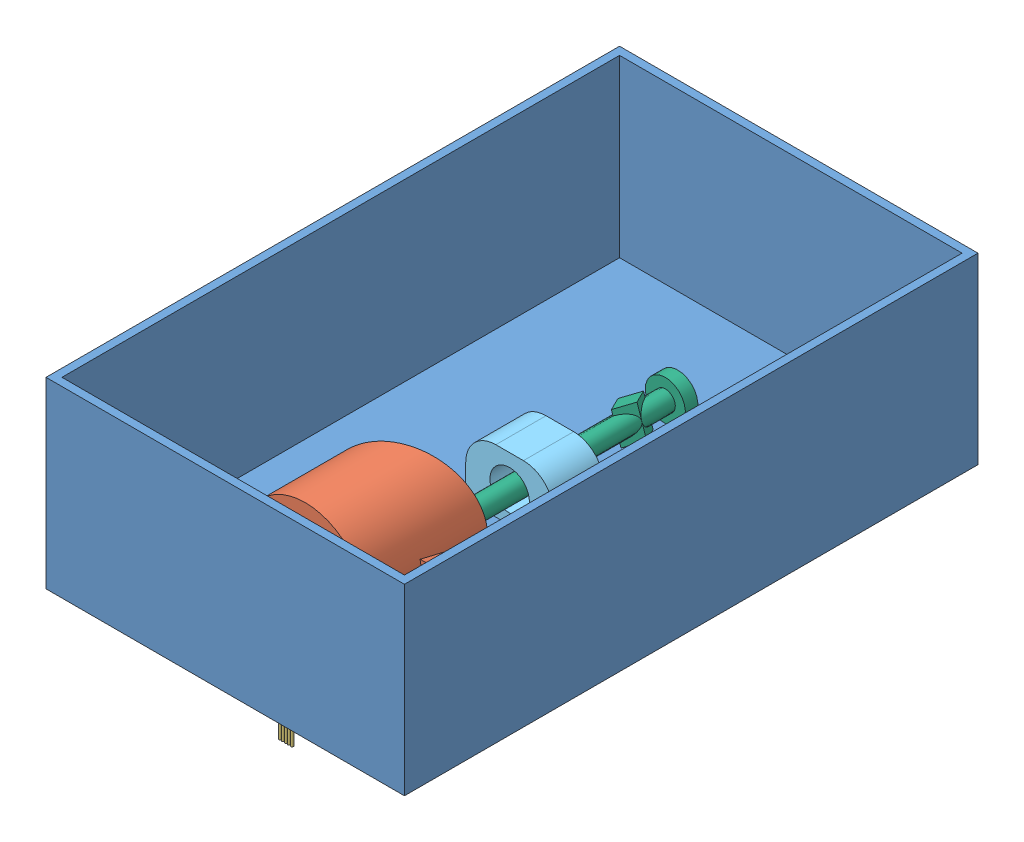
SolidWorks assembly Follower_Assembly, configuration Default. Lengths in mm.
Overall size (142.88 99.85 228.6).
7 component instances, 6 part files, 6 mates.
Components (placement in the parent):
- Basic-ForSizing-1: Basic-ForSizing [Default] at (72.7805 79.598 141.9377) size (142.88 73.02 228.6)
- cam-1: cam [Default] at (90.0846 104.598 263.6734) x (1 0 0) z (0 1 0) size (51 48.74 48)
- stepper_holder-1: stepper_holder [Default] at (70.8437 50.6752 228.5609) size (48 64 31.52)
  - Step Motor (28BYJ-48)-1: Step Motor (28BYJ-48) [Varsayılan] at (19.2409 45.9228 39.1125) size (42 61 29.02)
  - stepper_holder_28BYJ-48-1: stepper_holder_28BYJ-48 [Default] at (19.2409 28.9228 46.0671) size (48 34 24)
- piston_holder-1: piston_holder [Default] at (88.4561 79.598 170.8571) size (35 25 20)
- piston-1: piston [Default] at (89.6208 91.598 119.6742) x (0.94753 0.319668 0) z (0.319668 -0.94753 0) size (16 109 16)
Mates (geometry in assembly coordinates):
- Coincident1: coincident anti-aligned: plane of cam-1 through (87.5846 106.098 257.6734) normal (0 -1 0); plane of stepper_holder-1/Step Motor (28BYJ-48)-1 through (92.0846 106.098 257.6734) normal (0 1 0)
- Coincident2: coincident anti-aligned: plane of cam-1 through (90.0846 104.598 257.6734) normal (0 0 1); plane of stepper_holder-1/Step Motor (28BYJ-48)-1 through (90.0846 104.598 257.6734) normal (0 0 -1)
- Coincident4: coincident: plane of cam-1 through (87.5846 103.098 257.6734) normal (1 0 0); moEndPointRef_w of stepper_holder-1/Step Motor (28BYJ-48)-1
- Coincident5: coincident anti-aligned: plane of Basic-ForSizing-1 through (72.7805 79.598 141.9377) normal (0 1 0); plane of stepper_holder-1/stepper_holder_28BYJ-48-1 through (90.0846 79.598 274.6281) normal (0 -1 0)
- Coincident6: coincident anti-aligned: plane of Basic-ForSizing-1 through (72.7805 79.598 141.9377) normal (0 1 0); plane of piston_holder-1 through (88.4561 79.598 170.8571) normal (0 -1 0)
- Concentric1: concentric anti-aligned: circle of piston_holder-1; cylinder of piston-1 through (89.6208 91.598 219.6742) axis (0 0 -1) radius 4
